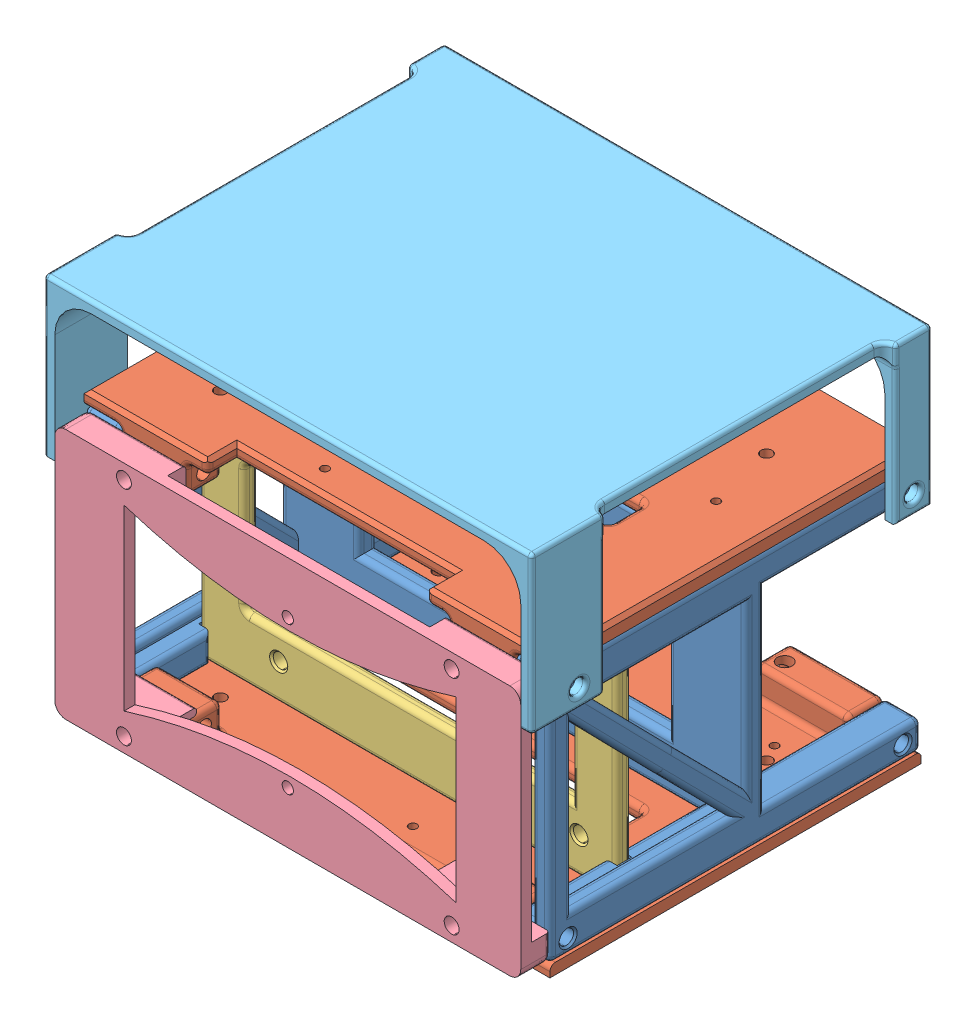
SolidWorks assembly ElecMount, configuration Default. Lengths in mm.
Overall size (134 107 110).
6 component instances, 5 part files, 15 mates.
Components (placement in the parent):
- mounting_base-1: mounting_base [Default] at (-18.14 15.9642 -2.2736) size (128 69 102)
- shield-1: shield [Default] at (-18.14 -10.5358 5.7264) x (0 -1 0) z (0 0 1) size (12 128 102)
- shield-2: shield [Default] at (-18.14 42.4642 5.7264) x (0 1 0) z (0 0 1) size (12 128 102)
- Arduino_New-1: Arduino_New [Default] at (-18.14 15.9642 27.7264) size (115 69 4)
- upper_energy_board-1: upper_energy_board [Default] at (-18.14 15.9642 64.7264) x (1 0 0) z (0 1 0) size (128 11 69)
- Wire_shading_part-1: Wire_shading_part [Default] at (40.86 81.4642 64.7264) x (-1 0 0) z (0 1 0) size (134 110 43)
Mates (geometry in assembly coordinates):
- Coincident1: coincident anti-aligned: plane of mounting_base-1 through (-82.14 -18.5358 2.7264) normal (0 -1 0); plane of shield-1 through (-18.14 -18.5358 5.7264) normal (0 1 0)
- Concentric1: concentric aligned: cylinder of mounting_base-1 through (45.86 -14.5358 51.7264) axis (-1 0 0) radius 2; cylinder of shield-1 through (45.86 -14.5358 51.7264) axis (-1 0 0) radius 2.025
- Coincident2: coincident anti-aligned: plane of mounting_base-1 through (-72.14 -18.5358 -45.2736) normal (1 0 0); plane of shield-1 through (-72.14 -18.5358 -45.2736) normal (-1 0 0)
- Coincident3: coincident anti-aligned: plane of mounting_base-1 through (35.86 50.4642 -45.2736) normal (-1 0 0); plane of shield-2 through (35.86 50.4642 -45.2736) normal (1 0 0)
- Concentric2: concentric anti-aligned: cylinder of mounting_base-1 through (45.86 46.4642 51.7264) axis (-1 0 0) radius 2; cylinder of shield-2 through (-82.14 46.4642 51.7264) axis (1 0 0) radius 2.025
- Coincident4: coincident aligned: plane of mounting_base-1 through (-18.14 15.9642 56.7264) normal (0 0 1); plane of shield-2 through (35.86 50.4642 56.7264) normal (0 0 1)
- Coincident5: coincident anti-aligned: plane of mounting_base-1 through (-18.14 15.9642 27.7264) normal (0 0 1); plane of Arduino_New-1 through (-18.14 15.9642 27.7264) normal (0 0 -1)
- Coincident6: coincident anti-aligned: plane of mounting_base-1 through (-75.64 -18.5358 31.7264) normal (1 0 0); plane of Arduino_New-1 through (-75.64 -18.5358 31.7264) normal (-1 0 0)
- Coincident7: coincident anti-aligned: plane of shield-1 through (-18.14 -18.5358 5.7264) normal (0 1 0); plane of Arduino_New-1 through (-75.64 -18.5358 31.7264) normal (0 -1 0)
- Concentric3: concentric anti-aligned: cylinder of shield-2 through (26.86 46.4642 53.2264) axis (0 0 1) radius 2.05; cylinder of upper_energy_board-1 through (26.86 46.4642 56.7254) axis (0 0 -1) radius 2.05
- Coincident8: coincident aligned: cylinder of shield-2 through (-63.14 46.4642 53.2264) axis (0 0 1) radius 2.05; circle of upper_energy_board-1
- Coincident9: coincident anti-aligned: plane of shield-2 through (35.86 50.4642 56.7264) normal (0 0 1); plane of upper_energy_board-1 through (-18.14 15.9642 56.7264) normal (0 0 -1)
- Concentric4: concentric aligned: cylinder of mounting_base-1 through (45.86 46.4642 51.7264) axis (-1 0 0) radius 2; cylinder of Wire_shading_part-1 through (48.86 46.4642 51.7264) axis (-1 0 0) radius 2
- Concentric5: concentric aligned: cylinder of mounting_base-1 through (45.86 46.4642 -40.2736) axis (-1 0 0) radius 2; cylinder of Wire_shading_part-1 through (48.86 46.4642 -40.2736) axis (-1 0 0) radius 2
- Coincident10: coincident anti-aligned: plane of mounting_base-1 through (45.86 50.4642 2.7264) normal (1 0 0); plane of Wire_shading_part-1 through (45.86 81.4642 64.7264) normal (-1 0 0)
